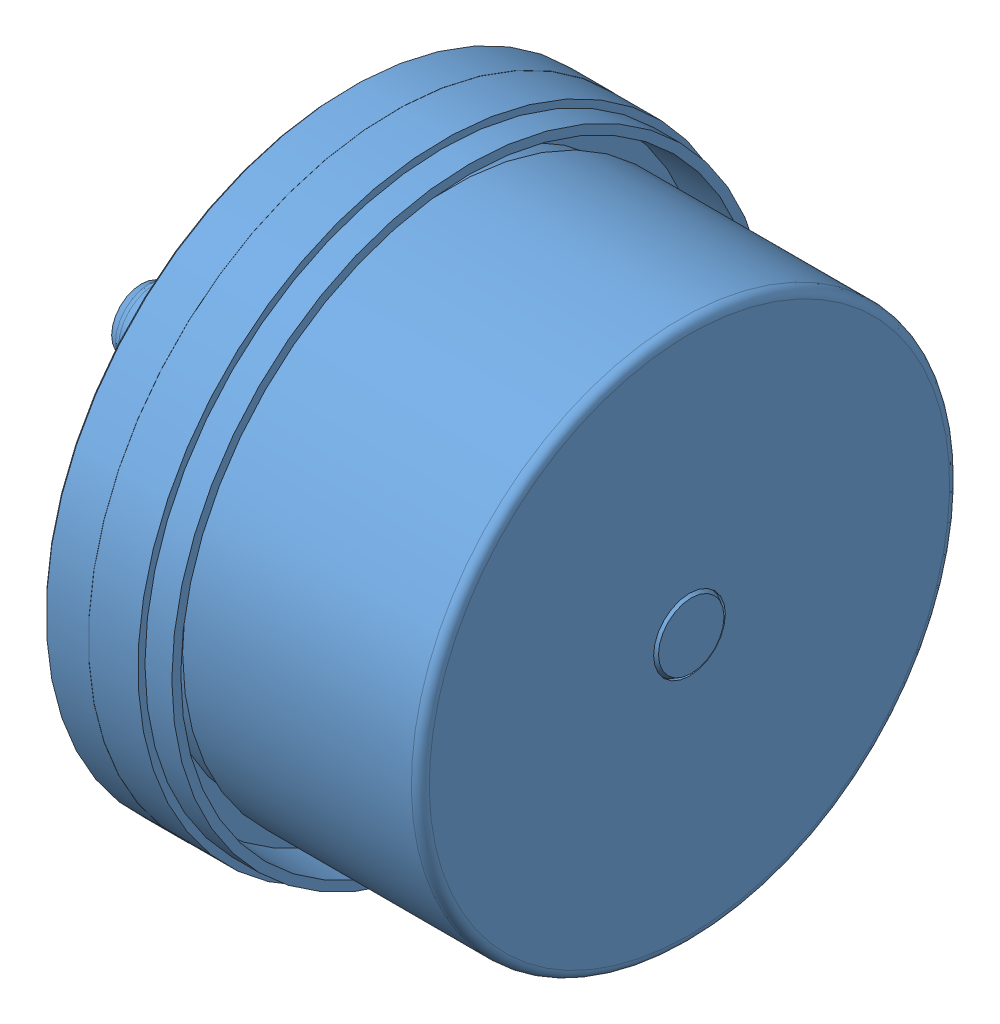
SolidWorks assembly EC60_motor_12_198_IP00_STEP, configuration Default. Lengths in mm.
Overall size (61.3 68 68).
7 component instances, 5 part files, 0 mates.
Components (placement in the parent):
- 1393671-1: 1393671 [Default] at origin size (61.3 68 68)
- 1393806_ASM-1: 1393806_ASM [Default] at (7.3675 -28 11.51) x (0 -1 0) z (0 0 -1) size (311 10.85 10.64) (hidden)
  - 1393805-1: 1393805 [Default] at origin size (301 4.37 9.4)
  - 1393804-1: 1393804 [Default] at (296 0 11.43) x (0 0 1) z (0 1 0) size (9.85 14 10.85)
- 1393835_ASM-1: 1393835_ASM [Default] at (10.0675 -245.4 -12.5) x (0 0 -1) z (1 0 0) size (9.68 311 14.4) (hidden)
  - 1393837-1: 1393837 [Default] at origin size (8.17 293.4 6.4)
  - 1393836-1: 1393836 [Default] at (-2.33 -79.7 -1) x (1 0 0) z (0 -1 0) size (9.6 14.4 19.6)
